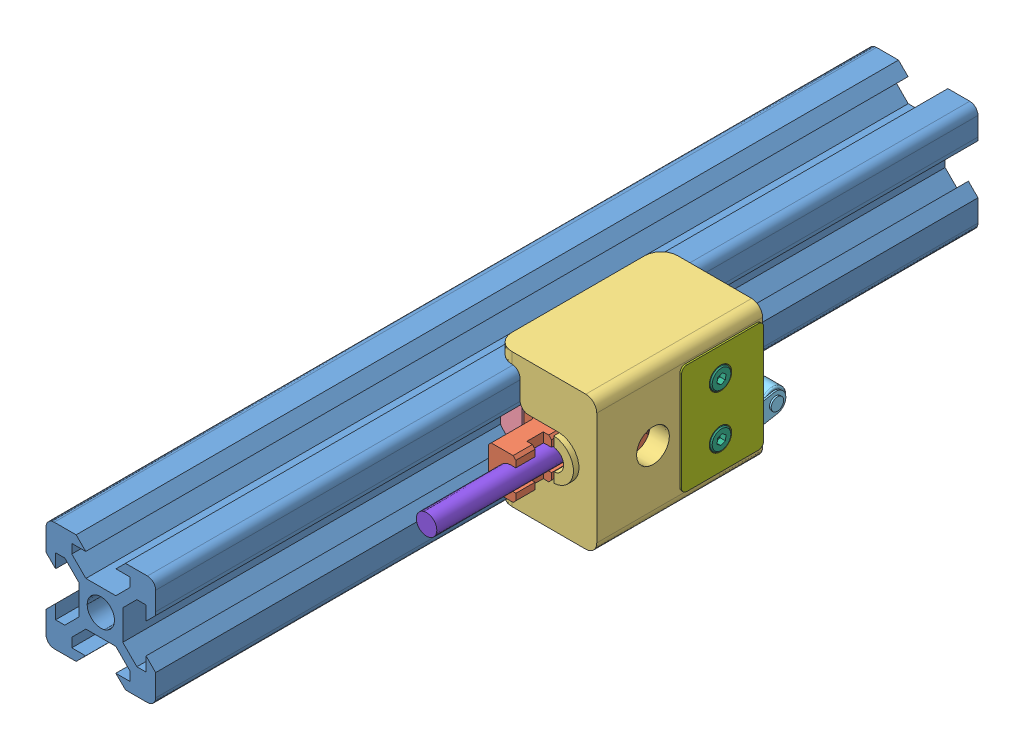
SolidWorks assembly TML Aufero_Laser_2 Limit Switch Y_Axis Holder Medium, configuration Default. Lengths in mm.
Overall size (34.51 24.5 150).
11 component instances, 9 part files, 6 mates.
Components (placement in the parent):
- AuFero 2020 V-slot-1: AuFero 2020 V-slot [Default] at (0 8.5854 -66.6262) size (20 20 150)
- TML Aufero_Laser_2 Y_Axis Limit Switch Medium Holder v1-1: TML Aufero_Laser_2 Y_Axis Limit Switch Medium Holder v1 [Default] at (10.0326 8.5882 3.7014) x (0 -1 0) z (1 0 0) size (20.5 38 8.5)
- TML Aufero_Laser_2 Y_Axis Limit Switch Medium Cap V1-1: TML Aufero_Laser_2 Y_Axis Limit Switch Medium Cap V1 [Default] at (20.5115 8.5885 -0.3281) x (0 -1 0) z (1 0 0) size (24.5 31.25 18.5)
- TML 2020 Slot Medium Nut -2: TML 2020 Slot Medium Nut  [Default] at (6.2461 8.5855 -13.3144) size (3.97 10.3 28)
- Microswitch 20mm-1: Microswitch 20mm [Default] at (17.2123 18.6337 -3.0212) x (1 0 0) z (0 1 0) size (6.4 23.41 21.8)
- socket head cap screw_am-6: socket head cap screw_am [B18.3.1M - 2 x 0.4 x 12 Hex SHCS -- 12NHX] at (24.5115 13.3885 -5.3281) x (-1 0 0) z (0 0.924225 0.381849) size (14 3.8 3.8)
- socket head cap screw_am-5: socket head cap screw_am [B18.3.1M - 2 x 0.4 x 12 Hex SHCS -- 12NHX] at (24.5115 3.7885 -5.3281) x (-1 0 0) z (0 0.924225 0.381849) size (14 3.8 3.8)
- socket head cap screw_am-1: socket head cap screw_am [B18.3.1M - 3 x 0.5 x 6 Hex SHCS -- 6NHX] at (14.5326 8.5882 6.7014) x (-1 0 0) z (0 0.924225 0.381849) size (9 5.5 5.5)
- Part2^TML Aufero_Laser_2 Limit Switch Y_Axis Holder Medium-1: Part2^TML Aufero_Laser_2 Limit Switch Y_Axis Holder Medium [Default] at origin (virtual)
- Microswitch 20mm mount test spacer-1: Microswitch 20mm mount test spacer [Default] at (20.3184 8.5546 -6.58) x (0 -1 0) z (1 0 0) size (20 15 4)
- Test Cable-1: Test Cable [Default] at (15.8165 8.5937 9.7737) size (3.75 3.75 30)
Mates (geometry in assembly coordinates):
- Concentric1: concentric anti-aligned: cylinder of TML Aufero_Laser_2 Y_Axis Limit Switch Medium Holder v1-1 through (14.0326 8.5882 6.7014) axis (-1 0 0) radius 1.8; cylinder of socket head cap screw_am-1 through (46.2826 8.5882 6.7014) axis (1 0 0) radius 2.75
- Coincident1: coincident anti-aligned: plane of TML Aufero_Laser_2 Y_Axis Limit Switch Medium Holder v1-1 through (11.5326 8.5882 6.7014) normal (1 0 0); plane of socket head cap screw_am-1 through (11.5326 7.5381 9.2431) normal (-1 0 0)
- Concentric2: concentric anti-aligned: cylinder of TML Aufero_Laser_2 Y_Axis Limit Switch Medium Cap V1-1 through (24.0115 3.7885 -5.3281) axis (-1 0 0) radius 1.3; cylinder of socket head cap screw_am-5 through (56.2615 3.7885 -5.3281) axis (1 0 0) radius 1.9
- Coincident2: coincident anti-aligned: plane of TML Aufero_Laser_2 Y_Axis Limit Switch Medium Cap V1-1 through (22.5115 3.7885 -5.3281) normal (1 0 0); plane of socket head cap screw_am-5 through (22.5115 3.063 -3.5721) normal (-1 0 0)
- Concentric3: concentric anti-aligned: cylinder of TML Aufero_Laser_2 Y_Axis Limit Switch Medium Cap V1-1 through (24.0115 13.3885 -5.3281) axis (-1 0 0) radius 1.3; cylinder of socket head cap screw_am-6 through (56.2615 13.3885 -5.3281) axis (1 0 0) radius 1.9
- Coincident3: coincident anti-aligned: plane of TML Aufero_Laser_2 Y_Axis Limit Switch Medium Cap V1-1 through (22.5115 13.3885 -5.3281) normal (1 0 0); plane of socket head cap screw_am-6 through (22.5115 12.663 -3.5721) normal (-1 0 0)
